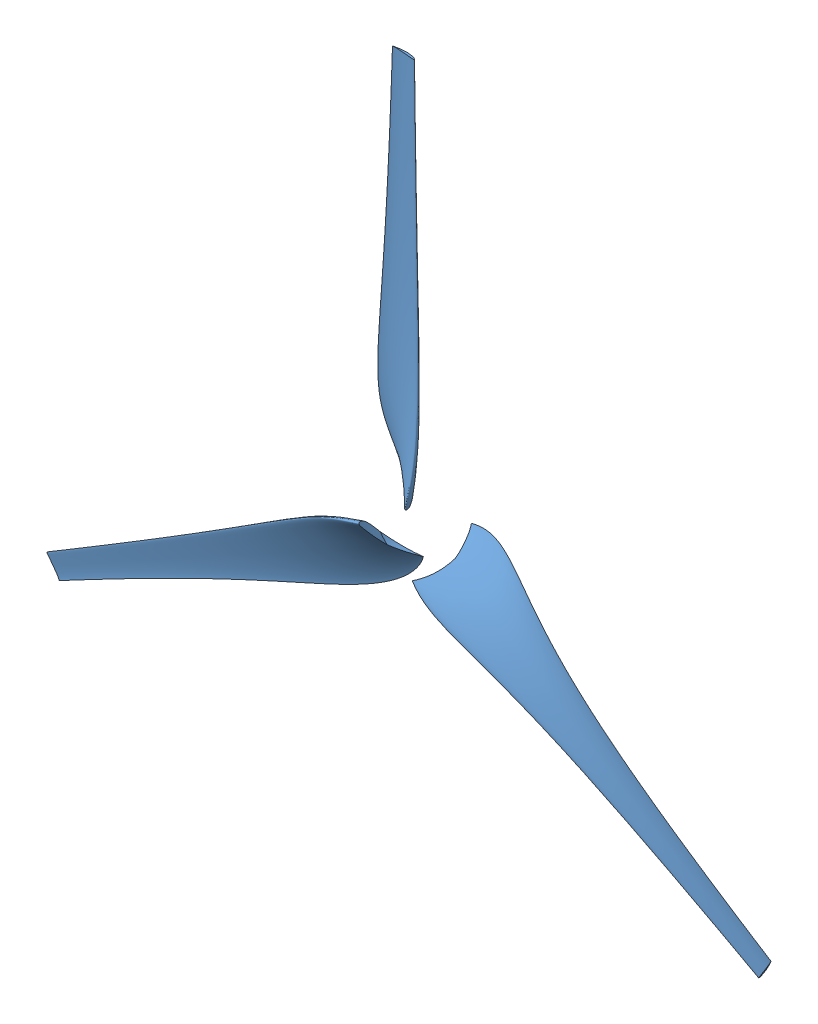
SolidWorks assembly celek, configuration Výchozí. Lengths in mm.
Overall size (2284.57 1989.36 1395.02).
3 component instances, 1 part files, 3 mates.
Components (placement in the parent):
- Nový list-2: Nový list [Výchozí] x (0 1 0) z (1 0 0) size (1368.75 127.07 260.66)
- Nový list-4: Nový list [Výchozí] x (0.866025 -0.5 0) z (-0.5 -0.866025 0) size (1368.75 127.07 260.66)
- Nový list-5: Nový list [Výchozí] x (-0.866025 -0.5 0) z (-0.5 0.866025 0) size (1368.75 127.07 260.66)
Mates (geometry in assembly coordinates):
- Sjednocená2: coincident aligned: plane of Nový list-2; plane of assembly through (0 0 0) normal (0 0 1)
- Sjednocená3: coincident aligned: plane of Nový list-2; plane of assembly through (0 0 0) normal (0 1 0)
- Sjednocená4: coincident: point of Nový list-2; point of assembly
